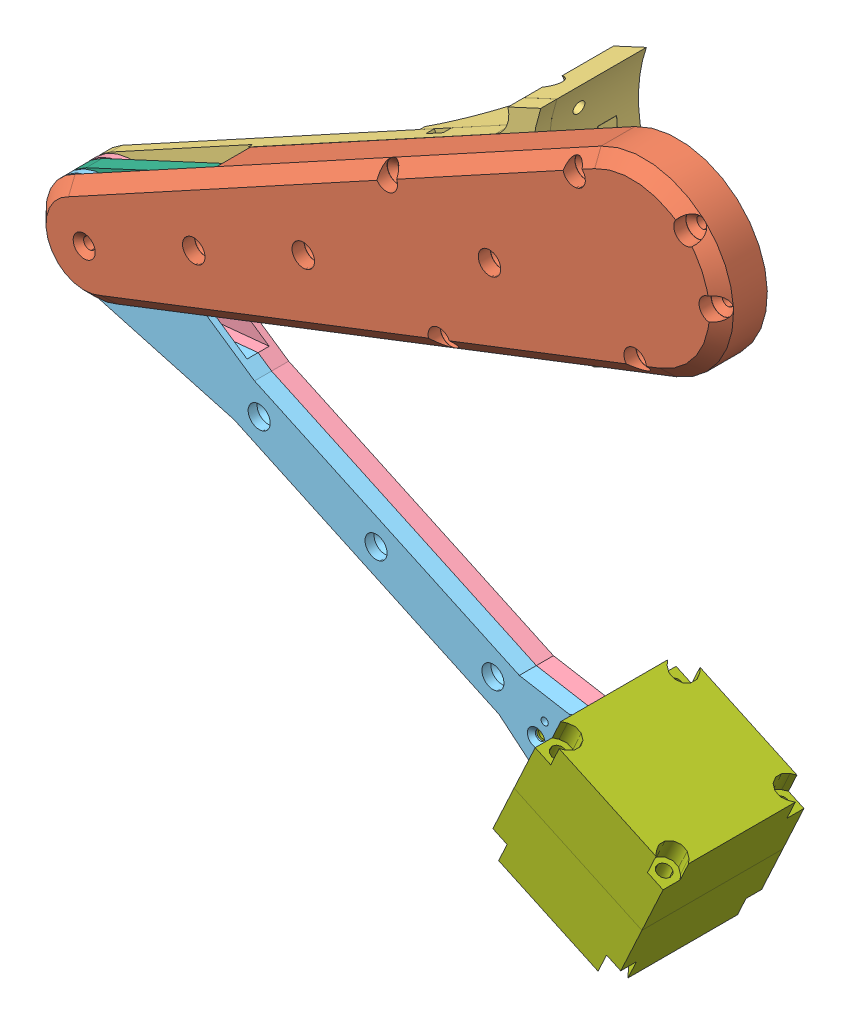
SolidWorks assembly leg-assembly, configuration Connecting Plate. Lengths in mm.
Overall size (187.54 169.83 41.55).
7 component instances, 7 part files, 20 mates.
Components (placement in the parent):
- 26t-s3m-pulley-1: 26t-s3m-pulley [Default] at (0 0 2.65) x (0 0 -1) z (-0.420313 -0.907379 0) size (7 25 25)
- sholder arm outer cover-2: sholder arm outer cover [Default] at (0 0 4.6878) x (0.421232 -0.906953 0) z (-0.906953 -0.421232 0) size (44.5 11.4 184.75)
- sholder arm inner cover-1: sholder arm inner cover [No nuts] at (0 0 -1.0122) x (0.421071 -0.907028 0) z (-0.907028 -0.421071 0) size (50.35 29.15 136.6)
- 26t-s3m-pulley-ankle-1: 26t-s3m-pulley-ankle [No nuts] at (-136.0541 -63.1607 2.3) x (0 0 1) z (-0.907379 0.420313 0) size (6.75 25 140.55)
- lower arm upper cover-1: lower arm upper cover [Default] at (-136.0541 -63.1607 6.65) x (-0.420313 -0.907379 0) z (0.907379 -0.420313 0) size (25 4.24 140.55)
- 125t-s3m-belt-straight-1: 125t-s3m-belt-straight [Default] at (-68.0271 -31.5803 2.65) x (-0.907028 -0.421071 0) z (0 0 1) size (175 25 4)
- 30mm-feet-housing-1: 30mm-feet-housing [30mm] at (11.9031 -131.6969 2.3) x (0.420313 0.907379 0) z (0 0 1) size (35 45.01 35)
Mates (geometry in assembly coordinates):
- Coincident34: coincident anti-aligned: plane of sholder arm outer cover-2 through (-136.0429 -63.1848 -1.0122) normal (0 0 -1); plane of sholder arm inner cover-1 through (-136.0541 -63.1607 -1.0122) normal (0 0 1)
- Coincident35: coincident aligned: plane of sholder arm outer cover-2 through (-130.7775 -74.5217 10.3878) normal (0.361224 -0.932479 0); plane of sholder arm inner cover-1 through (-131.5388 -74.8167 -5.0122) normal (0.361224 -0.932479 0)
- Coincident39: coincident aligned: line of 26t-s3m-pulley-1 through (0 0 -0.5) axis (0 0 1)
- Coincident40: coincident anti-aligned: plane of 26t-s3m-pulley-1 through (0 0 0) normal (0 0 -1)
- Distance1: distance = 1.0122 mm aligned: plane of sholder arm outer cover-2 through (-136.0429 -63.1848 -1.0122) normal (0 0 -1); plane of 26t-s3m-pulley-1 through (0 0 0) normal (0 0 -1)
- Concentric27: concentric anti-aligned: line of 26t-s3m-pulley-1 through (0 0 -0.5) axis (0 0 1); cylinder of sholder arm outer cover-2 through (0 0 10.3878) axis (0 0 -1) radius 22.25
- Concentric28: concentric anti-aligned: cylinder of sholder arm outer cover-2 through (0 0 10.3878) axis (0 0 -1) radius 22.25; cylinder of sholder arm inner cover-1 through (0 0 -5.0122) axis (0 0 1) radius 36
- Parallel2: parallel anti-aligned: plane of sholder arm inner cover-1 through (-136.0541 -63.1607 -1.6022) normal (0 0 1); plane of 26t-s3m-pulley-ankle-1 through (-136.0541 -63.1607 -1.6) normal (0 0 -1)
- Concentric29: concentric anti-aligned: cylinder of sholder arm inner cover-1 through (-136.0541 -63.1607 1.8978) axis (0 0 -1) radius 4; cylinder of 26t-s3m-pulley-ankle-1 through (-136.0541 -63.1607 0.15) axis (0 0 1) radius 6.05
- Coincident44: coincident anti-aligned: plane of 26t-s3m-pulley-ankle-1 through (-131.3701 -52.3656 5.15) normal (0 0 1); plane of lower arm upper cover-1 through (-136.0541 -63.1607 5.15) normal (0 0 -1)
- Concentric30: concentric aligned: cylinder of 26t-s3m-pulley-ankle-1 through (-136.0541 -63.1607 -1.6) axis (0 0 1) radius 12.5; cylinder of lower arm upper cover-1 through (-136.0541 -63.1607 5.15) axis (0 0 1) radius 12.5
- Parallel3: parallel aligned: plane of 26t-s3m-pulley-ankle-1 through (-129.0055 -52.8375 -1.6) normal (0.563888 0.825851 0); plane of lower arm upper cover-1 through (-129.0055 -52.8375 5.15) normal (0.563888 0.825851 0)
- Parallel4: parallel anti-aligned: plane of 26t-s3m-pulley-1 through (0 0 2.65) normal (0.907379 -0.420313 0); plane of 26t-s3m-pulley-ankle-1 through (-136.0541 -63.1607 2.3) normal (-0.907379 0.420313 0)
- Concentric31: concentric aligned: cylinder of 26t-s3m-pulley-1 through (0 0 7) axis (0 0 -1) radius 11.9215; cylinder of 125t-s3m-belt-straight-1 through (0 0 4.65) axis (0 0 -1) radius 11.25
- Coincident45: coincident anti-aligned: plane of 26t-s3m-pulley-1 through (0 0 2.65) normal (0 0 -1); plane of 125t-s3m-belt-straight-1 through (-68.0271 -31.5803 2.65) normal (0 0 1)
- Parallel5: parallel aligned: plane of sholder arm inner cover-1 through (0 0 -1.0122) normal (0.421071 -0.907028 0); plane of 125t-s3m-belt-straight-1 through (-68.0271 -31.5803 2.65) normal (0.421071 -0.907028 0)
- Coincident46: coincident anti-aligned: plane of 26t-s3m-pulley-ankle-1 through (-15.5896 -107.7535 93.0189) normal (0.907379 -0.420313 0); plane of 30mm-feet-housing-1 through (-19.8642 -116.9817 2.3) normal (-0.907379 0.420313 0)
- Concentric32: concentric anti-aligned: circle of 26t-s3m-pulley-ankle-1; circle of 30mm-feet-housing-1
- Parallel6: parallel anti-aligned: plane of 26t-s3m-pulley-ankle-1 through (-136.0541 -63.1607 -1.6) normal (0 0 -1); plane of 30mm-feet-housing-1 through (11.9031 -131.6969 2.3) normal (0 0 1)
- Symmetric1: symmetric aligned: plane of 26t-s3m-pulley-ankle-1 through (-136.0541 -63.1607 2.65) normal (0 0 1); plane of 125t-s3m-belt-straight-1 through (0 0 4.65) normal (0 0 1); plane of 125t-s3m-belt-straight-1 through (0 0 0.65) normal (0 0 -1)
